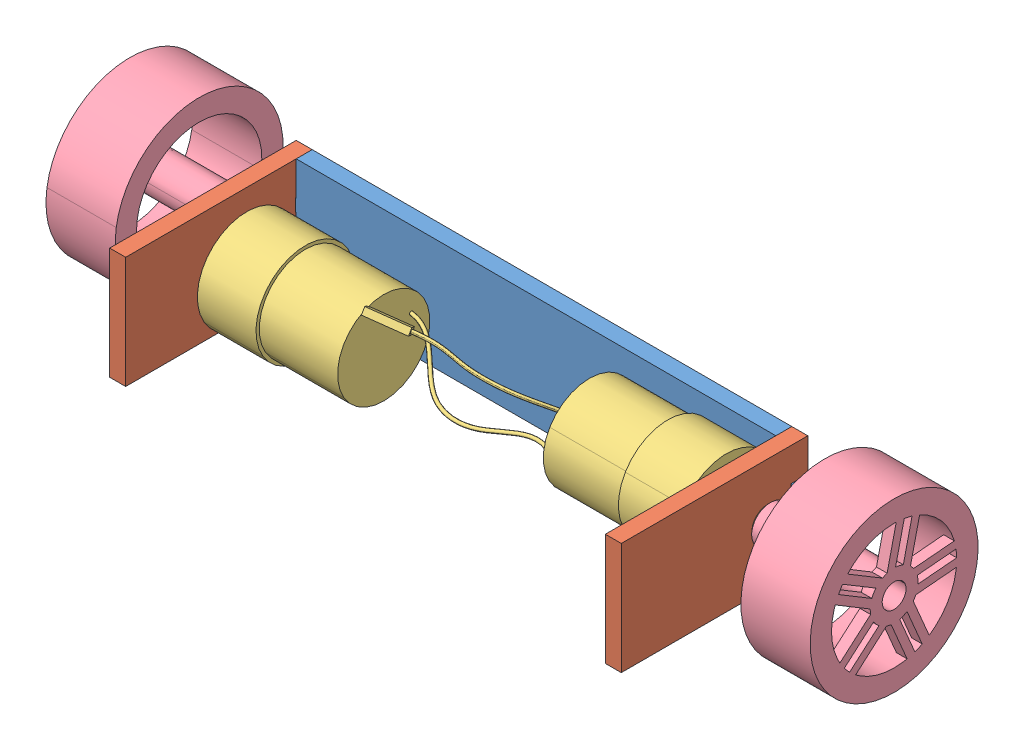
SolidWorks assembly Assem4, configuration Default. Lengths in mm.
Overall size (286.8 88.88 99.43).
7 component instances, 4 part files, 17 mates.
Components (placement in the parent):
- motor base-1: motor base [Default] at (58.4298 94.8342 186.7352) size (192.87 42 6)
- Part9-1: Part9 [Default] at (184.5127 93.1888 151.846) x (0 -1 0) z (-1 0 0) size (42 70 6)
- Part9-2: Part9 [Default] at (-1.4873 93.1888 151.846) x (0 -1 0) z (-1 0 0) size (42 70 6)
- motor-1: motor [Default] at (127.1127 108.9584 211.2852) x (0 0.859532 -0.511081) z (0 -0.511081 -0.859532) size (37.1 151.83 37.1)
- motor-2: motor [Default] at (49.9127 97.6124 211.2852) x (0 -0.859532 -0.511081) z (0 0.511081 -0.859532) size (37.1 151.83 37.1)
- wheel-basic-1: wheel-basic [Default] at (-54.8873 103.2854 201.7444) x (0 0.988315 -0.152427) z (0 -0.152427 -0.988315) size (63 46.5 63)
- wheel-basic-2: wheel-basic [Default] at (231.9127 103.2854 201.7444) x (0 -0.754568 -0.656222) z (0 0.656222 -0.754568) size (63 46.5 63)
Mates (geometry in assembly coordinates):
- Coincident1: coincident anti-aligned: plane of motor base-1 through (178.5127 124.0386 192.7352) normal (1 0 0); plane of Part9-1 through (178.5127 93.1888 151.846) normal (-1 0 0)
- Coincident3: coincident anti-aligned: line of motor base-1 through (178.5127 111.0386 186.7352) axis (0 1 0); line of Part9-1 through (178.5127 124.0386 186.7352) axis (0 -1 0)
- Coincident4: coincident anti-aligned: line of motor base-1 through (178.5127 82.0386 192.7352) axis (0 0 -1); line of Part9-1 through (178.5127 82.0386 186.7352) axis (0 0 1)
- Coincident5: coincident anti-aligned: plane of motor base-1 through (-1.4873 111.0386 192.7352) normal (-1 0 0); plane of Part9-2 through (-1.4873 93.1888 151.846) normal (1 0 0)
- Coincident6: coincident aligned: line of motor base-1 through (-1.4873 124.0386 192.7352) axis (0 0 -1); line of Part9-2 through (-1.4873 124.0386 256.7352) axis (0 0 -1)
- Coincident7: coincident aligned: line of motor base-1 through (-1.4873 124.0386 186.7352) axis (0 -1 0); line of Part9-2 through (-1.4873 124.0386 186.7352) axis (0 -1 0)
- Concentric1: concentric anti-aligned: cylinder of Part9-1 through (184.5127 103.2854 201.7444) axis (1 0 0) radius 6; cylinder of motor-1 through (185.4127 103.2854 201.7444) axis (-1 0 0) radius 6
- Concentric2: concentric aligned: circle of Part9-1; circle of motor-1
- Coincident8: coincident anti-aligned: plane of Part9-1 through (178.5127 93.1888 151.846) normal (-1 0 0); plane of motor-1 through (178.5127 108.9584 211.2852) normal (1 0 0)
- Tangent1: tangent anti-aligned: plane of motor base-1 through (58.4298 94.8342 192.7352) normal (0 0 1); cylinder of motor-1 through (178.5127 108.9584 211.2852) axis (-1 0 0) radius 18.55
- Concentric3: concentric aligned: cylinder of Part9-2 through (-1.4873 103.2854 201.7444) axis (1 0 0) radius 6; cylinder of motor-2 through (-8.3873 103.2854 201.7444) axis (1 0 0) radius 6
- Coincident9: coincident anti-aligned: plane of Part9-2 through (-1.4873 93.1888 151.846) normal (1 0 0); plane of motor-2 through (-1.4873 97.6124 211.2852) normal (-1 0 0)
- Tangent2: tangent anti-aligned: plane of motor base-1 through (58.4298 94.8342 192.7352) normal (0 0 1); cylinder of motor-2 through (-1.4873 97.6124 211.2852) axis (1 0 0) radius 18.55
- Concentric4: concentric: cylinder of motor-2 through (-23.8873 103.2854 201.7444) axis (1 0 0) radius 2.95; cylinder of wheel-basic-1 through (-8.3873 103.2854 201.7444) axis (-1 0 0) radius 4.5
- Coincident12: coincident anti-aligned: plane of motor-2 through (-8.3873 103.2854 201.7444) normal (-1 0 0); plane of wheel-basic-1 through (-8.3873 103.2854 201.7444) normal (1 0 0)
- Concentric5: concentric: cylinder of motor-1 through (200.9127 103.2854 201.7444) axis (-1 0 0) radius 2.95; cylinder of wheel-basic-2 through (185.4127 103.2854 201.7444) axis (1 0 0) radius 4.5
- Coincident13: coincident anti-aligned: plane of motor-1 through (185.4127 103.2854 201.7444) normal (1 0 0); plane of wheel-basic-2 through (185.4127 103.2854 201.7444) normal (-1 0 0)
